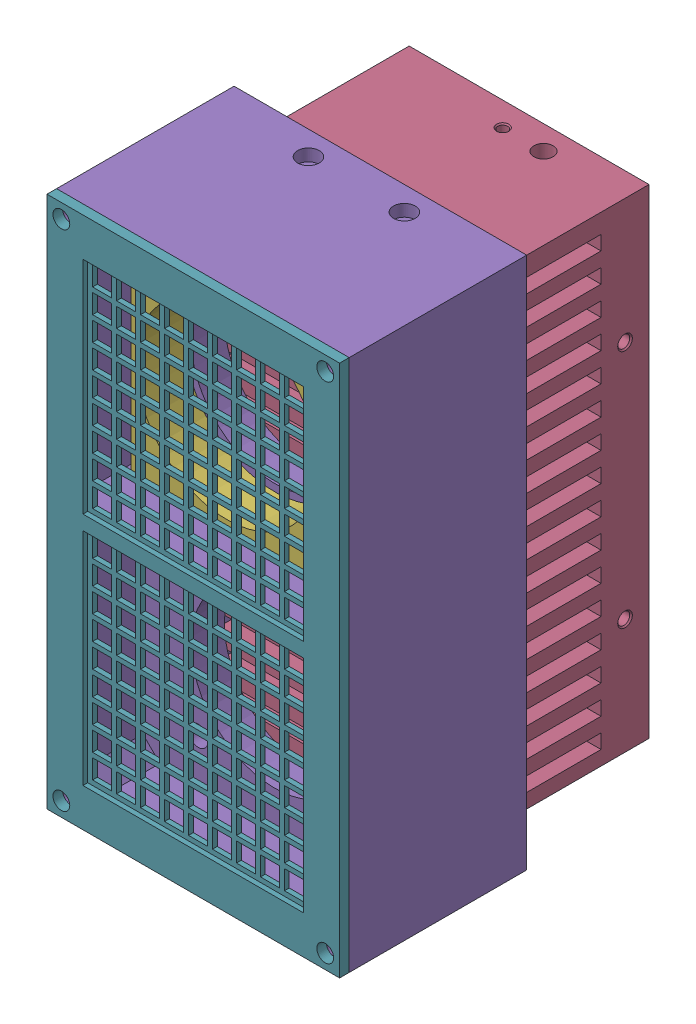
SolidWorks assembly assembly_LEDs_openSIM_V2.0, configuration Default. Lengths in mm.
Overall size (61 111 76.4).
7 component instances, 5 part files, 18 mates.
Components (placement in the parent):
- PT54_20200728_openSIM_V2.0-1: PT54_20200728_openSIM_V2.0 [Default] at (28.5132 157.2818 69.4063) x (1 0 0) z (0 0 -1) size (26.5 16 6.4)
- PT54_20200728_openSIM_V2.0-2: PT54_20200728_openSIM_V2.0 [Default] at (28.5132 127.2818 69.4063) x (1 0 0) z (0 0 -1) size (26.5 16 6.4)
- PT54_20200728_openSIM_V2.0-3: PT54_20200728_openSIM_V2.0 [Default] at (28.5132 97.2818 69.4063) x (1 0 0) z (0 0 -1) size (26.5 16 6.4)
- heat_sink_openSIM_V2.0-1: heat_sink_openSIM_V2.0 [Default] at (26.4132 69.2818 69.4063) size (50 100 40)
- fan_holder_openSIM_V2.0-1: fan_holder_openSIM_V2.0 [Default] at (20.9132 63.7818 100.4063) size (61 111 39)
- fan_openSIM_V2.0-1: fan_openSIM_V2.0 [Default] at (31.4132 126.7818 122.4063) size (40 40 10)
- fan_protection_openSIM_V2.0-1: fan_protection_openSIM_V2.0 [Default] at (81.9132 63.7818 137.4063) x (0 1 0) z (0 0 1) size (111 61 2)
Mates (geometry in assembly coordinates):
- Coincident1: coincident anti-aligned: plane of PT54_20200728-3 through (28.5132 97.2818 69.4063) normal (0 0 1); plane of heat_sink__20200728_MHAtest_20200728-1 through (26.4132 69.2818 69.4063) normal (0 0 -1)
- Concentric1: concentric anti-aligned: circle of PT54_20200728-3; circle of heat_sink__20200728_MHAtest_20200728-1
- Concentric2: concentric anti-aligned: circle of PT54_20200728-3; circle of heat_sink__20200728_MHAtest_20200728-1
- Concentric3: concentric aligned: circle of PT54_20200728-2; circle of heat_sink__20200728_MHAtest_20200728-1
- Concentric4: concentric aligned: circle of PT54_20200728-2; circle of heat_sink__20200728_MHAtest_20200728-1
- Concentric5: concentric aligned: circle of PT54_20200728-1; circle of heat_sink__20200728_MHAtest_20200728-1
- Concentric6: concentric aligned: circle of PT54_20200728-1; circle of heat_sink__20200728_MHAtest_20200728-1
- Concentric7: concentric anti-aligned: circle of heat_sink__20200728_MHAtest_20200728-1; circle of fan_holder-1
- Concentric8: concentric anti-aligned: circle of heat_sink__20200728_MHAtest_20200728-1; cylinder of fan_holder-1 through (41.4132 174.7818 105.4063) axis (0 -1 0) radius 1.1
- Width1: width anti-aligned: plane of fan_holder-1 through (20.9132 174.7818 115.4063) normal (0 1 0); plane of heat_sink__20200728_MHAtest_20200728-1 through (20.9132 63.7818 115.4063) normal (0 -1 0); plane of fan_holder-1 through (26.4132 69.2818 109.4063) normal (0 -1 0); plane of heat_sink__20200728_MHAtest_20200728-1 through (26.4132 169.2818 109.4063) normal (0 1 0)
- Coincident3: coincident anti-aligned: plane of PT54_20200728-2 through (28.5132 127.2818 69.4063) normal (0 0 1); plane of heat_sink__20200728_MHAtest_20200728-1 through (26.4132 69.2818 69.4063) normal (0 0 -1)
- Coincident4: coincident anti-aligned: plane of PT54_20200728-1 through (28.5132 157.2818 69.4063) normal (0 0 1); plane of heat_sink__20200728_MHAtest_20200728-1 through (26.4132 69.2818 69.4063) normal (0 0 -1)
- Concentric10: concentric aligned: cylinder of fan_holder-1 through (67.4132 130.7818 117.4063) axis (0 0 1) radius 2.1; cylinder of fan-1 through (67.4132 130.7818 122.4063) axis (0 0 1) radius 1
- Concentric11: concentric aligned: cylinder of fan_holder-1 through (67.4132 162.7818 117.4063) axis (0 0 1) radius 2.1; cylinder of fan-1 through (67.4132 162.7818 122.4063) axis (0 0 1) radius 1
- Coincident5: coincident anti-aligned: plane of fan_holder-1 through (20.9132 63.7818 122.4063) normal (0 0 1); plane of fan-1 through (31.4132 126.7818 122.4063) normal (0 0 -1)
- Coincident6: coincident anti-aligned: plane of fan_holder-1 through (20.9132 63.7818 137.4063) normal (0 0 1); plane of fan_protection-1 through (81.9132 63.7818 137.4063) normal (0 0 -1)
- Concentric12: concentric aligned: circle of fan_holder-1; circle of fan_protection-1
- Concentric13: concentric aligned: circle of fan_holder-1; circle of fan_protection-1
